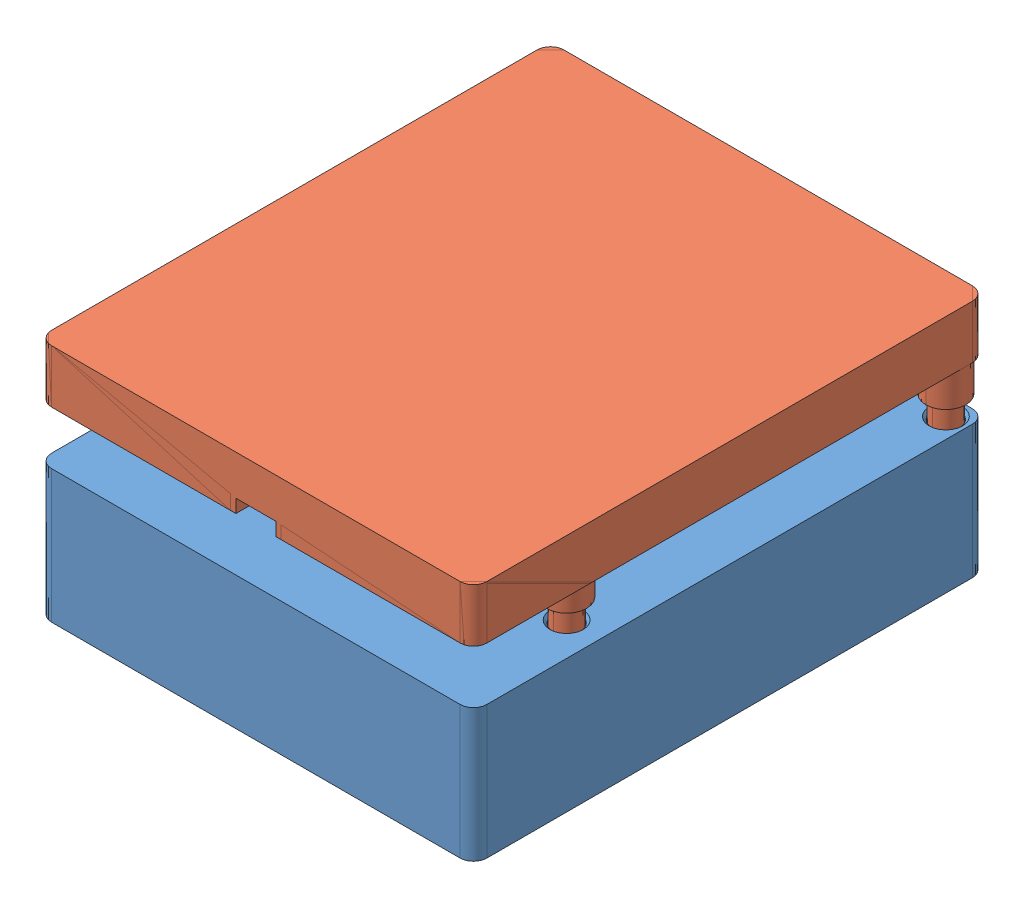
SolidWorks assembly Ensamble general, configuration Predeterminado. Lengths in mm.
Overall size (32.71 18 41.81).
3 component instances, 3 part files, 6 mates.
Components (placement in the parent):
- Base Motor.step-1: Base Motor.step [Predeterminado] at origin size (32.71 10 38.5)
- Cubierta Frontal.step-1: Cubierta Frontal.step [Predeterminado] at (0 11 0) size (32.71 12 38.5)
- Acople Engranaje.step-1: Acople Engranaje.step [Predeterminado] at (0 6.75 0) x (0.744083 0 0.668088) z (-0.668088 0 0.744083) size (18.5 5 17.5)
Mates (geometry in assembly coordinates):
- Coincidente1: coincident anti-aligned: plane of Cubierta Frontal.step-1 through (14.8564 1 -8.25) normal (0 -1 0); plane of Base Motor.step-1 through (-13.8564 1 19.25) normal (0 1 0)
- Coincidente2: coincident: line of Base Motor.step-1 through (16.672 0 0) axis (0 0 1); point of Acople Engranaje.step-1
- Paralelo1: parallel anti-aligned: plane of Base Motor.step-1 through (0 5 0) normal (0 1 0); plane of Acople Engranaje.step-1 through (0 5.5 0) normal (0 -1 0)
- Concéntrica1: concentric aligned: cylinder of Base Motor.step-1 through (14.8564 0.1716 -8.25) axis (0 1 0) radius 1.05; cylinder of Cubierta Frontal.step-1 through (14.8564 1 -8.25) axis (0 1 0) radius 1
- Concéntrica2: concentric aligned: cylinder of Base Motor.step-1 through (-13.8564 3 19.25) axis (0 1 0) radius 1.05; cylinder of Cubierta Frontal.step-1 through (-13.8564 1 19.25) axis (0 1 0) radius 1
- Distancia1: distance = 0.5 mm anti-aligned: plane of Acople Engranaje.step-1 through (0 5.5 0) normal (0 -1 0); plane of Base Motor.step-1 through (0 5 0) normal (0 1 0)
